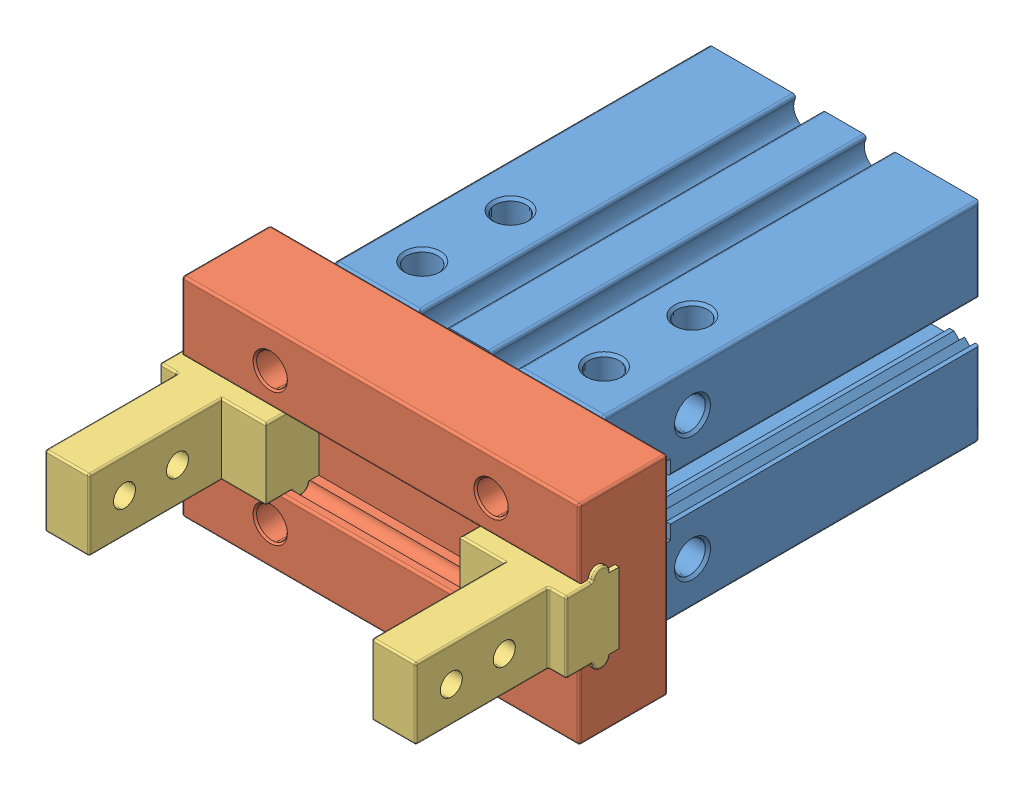
SolidWorks assembly mo kep2, configuration Default. Lengths in mm.
Overall size (46 23.6 69.5).
4 component instances, 3 part files, 6 mates.
Components (placement in the parent):
- NMHZ2-16D cylinder-1: NMHZ2-16D cylinder [Default] at (21.7978 22.616 7.9442) size (30.6 23.6 42.5)
- NMHZ2-16D Slipway-1: NMHZ2-16D Slipway [Default] at (21.7978 22.616 50.4442) size (45 23.6 10)
- NMHZ2-16D air claw-1: NMHZ2-16D air claw [Default] at (32.7978 22.616 58.4442) size (12 10 21)
- NMHZ2-16D air claw-2: NMHZ2-16D air claw [Default] at (10.7978 22.616 58.4442) x (-1 0 0) z (0 0 1) size (12 10 21)
Mates (geometry in assembly coordinates):
- Concentric1: concentric aligned: cylinder of NMHZ2-16D cylinder-1 through (34.2978 30.116 15.9442) axis (0 0 -1) radius 1.75; cylinder of NMHZ2-16D Slipway-1 through (34.2978 30.116 60.4442) axis (0 0 -1) radius 1.75
- Concentric2: concentric aligned: cylinder of NMHZ2-16D cylinder-1 through (34.2978 15.116 15.9442) axis (0 0 -1) radius 1.75; cylinder of NMHZ2-16D Slipway-1 through (34.2978 15.116 60.4442) axis (0 0 -1) radius 1.75
- Coincident1: coincident anti-aligned: plane of NMHZ2-16D cylinder-1 through (21.7978 22.616 50.4442) normal (0 0 1); plane of NMHZ2-16D Slipway-1 through (21.7978 22.616 50.4442) normal (0 0 -1)
- Concentric3: concentric anti-aligned: cylinder of NMHZ2-16D Slipway-1 through (-0.7022 26.616 58.4442) axis (1 0 0) radius 1; cylinder of NMHZ2-16D air claw-1 through (44.7978 26.616 58.4442) axis (-1 0 0) radius 1
- Concentric4: concentric anti-aligned: cylinder of NMHZ2-16D Slipway-1 through (-0.7022 18.616 58.4442) axis (1 0 0) radius 1; cylinder of NMHZ2-16D air claw-1 through (44.7978 18.616 58.4442) axis (-1 0 0) radius 1
- LimitDistance1: limit distance = 11 mm anti-aligned: plane of NMHZ2-16D air claw-1 through (32.7978 22.616 58.4442) normal (-1 0 0); plane of NMHZ2-16D cylinder-1 through (21.7978 22.616 7.9442) normal (1 0 0)
